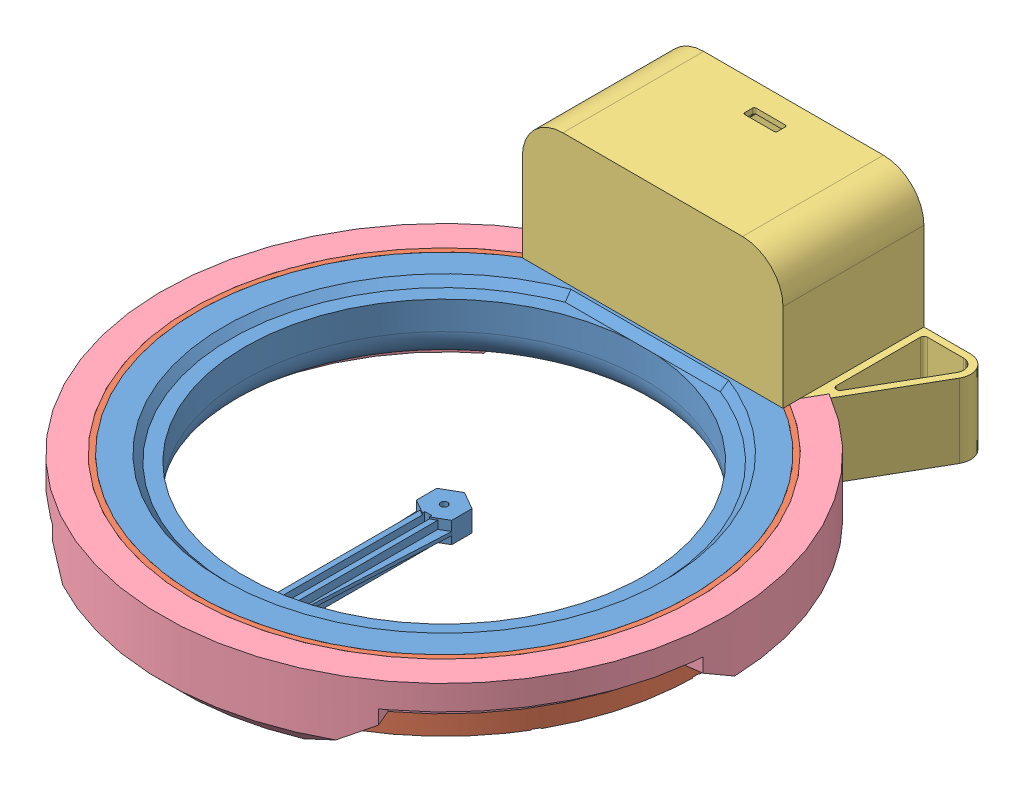
SolidWorks assembly 悬浮时钟, configuration 默认. Lengths in mm.
Overall size (218.04 57.5 218.04).
4 component instances, 4 part files, 9 mates.
Components (placement in the parent):
- 钟体-1: 钟体 [默认] at (-102.4958 -1.641 -56.4612) x (1 0 0) z (0 1 0) size (140 139.53 19.11)
- 悬浮钟外罩-1: 悬浮钟外罩 [默认] at (-102.4958 -7.641 63.5388) x (-1 0 0) z (0 0 -1) size (143 19 162.75)
- 底座-2: 底座 [默认] at (-102.7804 23.182 -38.6433) size (110.56 57.5 40)
- 外壳装饰环-1: 外壳装饰环 [默认] at (-102.4958 11.359 63.5388) x (-0.492424 0 0.870356) z (0.870356 0 0.492424) size (160 21 160)
Mates (geometry in assembly coordinates):
- 同心2: concentric: cylinder of assembly; cylinder of assembly; cylinder of 钟体-1 through (-102.4958 7.359 63.5388) axis (0 1 0) radius 70; cylinder of 悬浮钟外罩-1 through (-102.4958 11.359 63.5388) axis (0 -1 0) radius 70
- 重合4: coincident: plane of assembly; plane of assembly; plane of 钟体-1 through (-102.4958 11.359 63.5388) normal (0 1 0); plane of 底座-2 through (-139.4958 11.359 -34.1433) normal (0 -1 0)
- 同心3: concentric: cylinder of assembly; cylinder of assembly; cylinder of 钟体-1 through (-102.4958 8.359 63.5388) axis (0 1 0) radius 56.5; cylinder of 底座-2 through (-102.4958 -4.641 63.5388) axis (0 -1 0) radius 71.5
- 平行2: parallel: line of assembly; line of assembly; line of 钟体-1 through (-80.1224 11.359 5.1805) axis (-1 0 0); line of 底座-2 through (-139.4958 11.359 4.3567) axis (1 0 0)
- 重合6: coincident: plane of assembly; plane of assembly; plane of 钟体-1 through (-102.4958 11.359 63.5388) normal (0 1 0); plane of 悬浮钟外罩-1 through (-102.4958 11.359 63.5388) normal (0 1 0)
- 重合7: coincident: plane of assembly; plane of assembly; plane of 钟体-1 through (-133.9958 7.359 1.2812) normal (-1 0 0); plane of 悬浮钟外罩-1 through (-133.9958 1.359 -19.9363) normal (1 0 0)
- 同心4: concentric: cylinder of assembly; cylinder of assembly; cylinder of 悬浮钟外罩-1 through (-102.4958 11.359 63.5388) axis (0 -1 0) radius 71.5; cylinder of 外壳装饰环-1 through (-102.4958 -7.641 63.5388) axis (0 1 0) radius 71.5
- 重合8: coincident: plane of assembly; plane of assembly; plane of 悬浮钟外罩-1 through (-102.4958 -7.641 63.5388) normal (0 -1 0); plane of 外壳装饰环-1 through (-102.4958 -7.641 63.5388) normal (0 1 0)
- 平行3: parallel: plane of assembly; plane of assembly; plane of 底座-2 through (-65.4958 55.2376 2.3567) normal (0.866025 0 0.5); plane of 外壳装饰环-1 through (-102.4958 34.359 63.5388) normal (-0.866025 0 -0.5)
